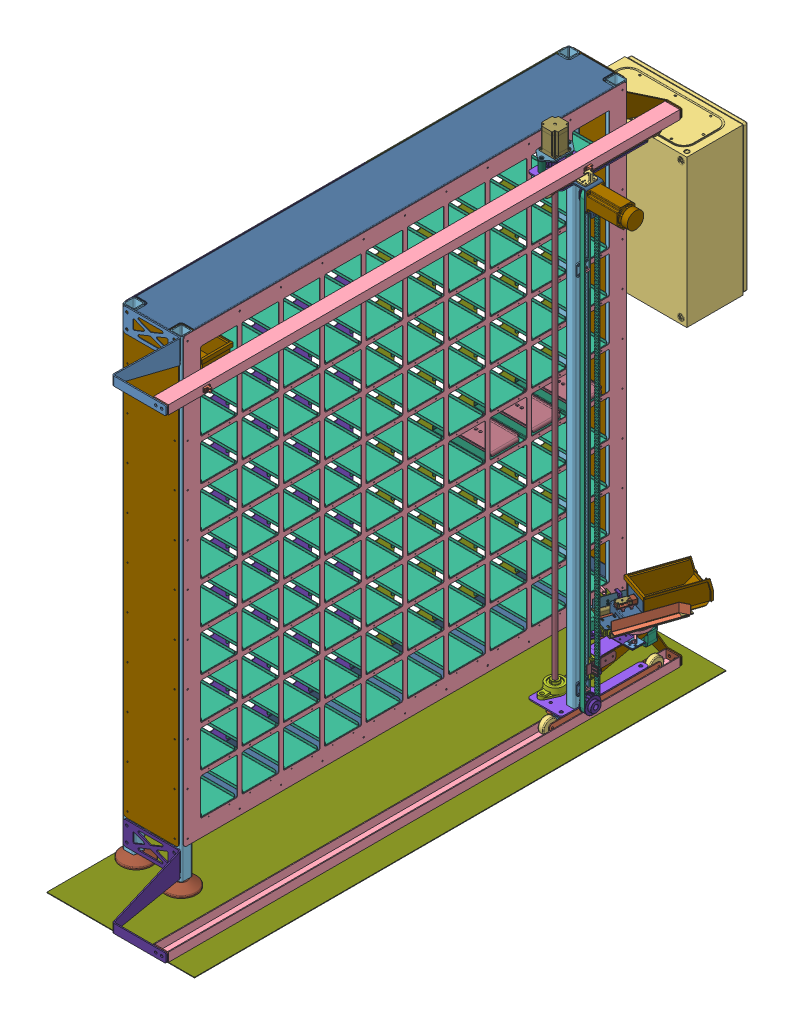
SolidWorks assembly T00000-000-R01, configuration Default. Lengths in mm.
Overall size (585.3 1705.5 1964.8).
272 component instances, 76 part files, 38 mates.
Components (placement in the parent):
- T00001-000-R00-1: T00001-000-R00 [Default] at (541.221 27.0951 939.139) size (309.78 1703.5 1800.8) (flexible)
  - T00118-000-R00-1: T00118-000-R00 [Default] at (157.9488 226.0018 -468.9511) size (25 25 300)
  - T00119-DXF-R00-1: T00119-DXF-R00 [Default] at (145.4488 226.0018 -318.9511) x (0 0 1) z (0 -1 0) size (380 3 25)
  - T00119-DXF-R00-2: T00119-DXF-R00 [Default] at (173.4488 226.0018 -318.9511) x (0 0 -1) z (0 1 0) size (380 3 25)
  - T00103-E00-R00-1: T00103-E00-R00 [Default] at (157.9488 226.0018 -138.9511) x (0 -0.996374 0.085085) z (0 0.085085 0.996374) size (50 22 50)
  - T00103-E00-R00-2: T00103-E00-R00 [Default] at (157.9488 226.0018 -498.9511) x (0 -1 0) z (0 0 1) size (50 22 50)
  - T00117-000-R00-1: T00117-000-R00 [Default] at (157.9488 198.0018 -560.9511) size (50 30 1732)
  - T00112-000-R00-1: T00112-000-R00 [50 x 30 x 2.6x1700] at (142.9488 1012.5018 -263.9511) x (1 0 0) z (0 -1 0) size (30 50 1540)
  - T00109-E00-R00-1: T00109-E00-R00 [HGR15R400CE20] at (157.9488 1772.5018 -263.9511) x (1 0 0) z (0 1 0) size (15 15 1530)
  - T00100-E00-R00-4: T00100-E00-R00 [Default] at (82.9488 242.5018 -238.9511) x (0 1 0) z (0 0 1) size (65.14 65.88 113)
  - T00120-DXF-R00-1: T00120-DXF-R00 [Default] at (100.4488 238.5018 -238.9511) x (0 0 -1) z (-1 0 0) size (300 4 115)
  - T00120-DXF-R00-2: T00120-DXF-R00 [Default] at (100.4488 1782.5018 -238.9511) x (0 0 -1) z (-1 0 0) size (300 4 115)
  - T00100-E00-R00-2: T00100-E00-R00 [Default] at (82.9488 1782.5018 -238.9511) x (0 -1 0) z (0 0 -1) size (65.14 65.88 113)
  - T00160-E00-R00-8: T00160-E00-R00 [Default] at (216.9488 1755.5018 -238.9511) x (0 0 1) z (-1 0 0) size (60 69 159.8)
  - T00121-0A4-R00-1: T00121-0A4-R00 [Default] at (216.9488 1751.5018 -238.9511) x (0 0 -1) z (0 -1 0) size (300 74 94)
  - T00103-E00-R00-3: T00103-E00-R00 [Default] at (157.9488 1803.0018 -138.9511) x (0 -1 0) z (0 0 1) size (50 22 50)
  - T00103-E00-R00-4: T00103-E00-R00 [Default] at (157.9488 1803.0018 -498.9511) x (0 0.952135 0.305677) z (0 0.305677 -0.952135) size (50 22 50)
  - T00119-DXF-R00-3: T00119-DXF-R00 [Default] at (173.4488 1803.0018 -318.9511) x (0 0 1) z (0 -1 0) size (380 3 25)
  - T00119-DXF-R00-4: T00119-DXF-R00 [Default] at (145.4488 1803.0018 -318.9511) x (0 0 -1) z (0 1 0) size (380 3 25)
  - T00118-000-R00-2: T00118-000-R00 [Default] at (157.9488 1803.0018 -168.9511) x (1 0 0) z (0 0 -1) size (25 25 300)
  - T00117-000-R00-2: T00117-000-R00 [Default] at (157.9488 1833.5018 -560.9511) x (-1 0 0) z (0 0 1) size (50 30 1732)
  - T00122-DXF-R00-1: T00122-DXF-R00 [Default] at (157.9488 213.0018 1175.0489) size (50 30 4)
  - T00122-DXF-R00-2: T00122-DXF-R00 [Default] at (157.9488 213.0018 -560.9511) size (50 30 4)
  - T00122-DXF-R00-3: T00122-DXF-R00 [Default] at (157.9488 1818.5018 -564.9511) x (-1 0 0) z (0 0 -1) size (50 30 4)
  - T00122-DXF-R00-4: T00122-DXF-R00 [Default] at (157.9488 1818.5018 1175.0489) size (50 30 4)
  - T00106-E00-R00-6: T00106-E00-R00 [Default] at (82.8989 1862.7018 -130.4663) x (-0.013505 0 0.999909) z (0 -1 0) size (56.4 57 96.6)
  - T00123-000-R00-1: T00123-000-R00 [Default] at (82.341 1823.9018 -238.9552) x (1 0 0) z (0 -1 0) size (15 15 1615)
  - T00124-DXF-R00-1: T00124-DXF-R00 [Default] at (82.341 1825.5018 -238.9552) x (-0.013505 0 0.999909) z (-0.999909 0 -0.013505) size (110 4 65)
  - T00104-E00-R00-1: T00104-E00-R00 [Default] at (82.9488 1786.5018 -193.9511) x (0 1 0) z (0 0 1) size (35 20 20)
  - T00104-E00-R00-2: T00104-E00-R00 [Default] at (82.9488 1786.5018 -283.9511) x (0 1 0) z (0 0 1) size (35 20 20)
  - T00101-E00-R00-1: T00101-E00-R00 [Default] at (112.9488 1791.0018 -193.9511) size (22 7 22)
  - T00101-E00-R00-2: T00101-E00-R00 [Default] at (112.9488 1791.0018 -283.9511) size (22 7 22)
  - T00101-E00-R00-3: T00101-E00-R00 [Default] at (112.9488 1798.0018 -283.9511) x (-0.837169 0 -0.546944) z (-0.546944 0 0.837169) size (22 7 22)
  - T00101-E00-R00-4: T00101-E00-R00 [Default] at (112.9488 1798.0018 -193.9511) x (-0.837169 0 -0.546944) z (-0.546944 0 0.837169) size (22 7 22)
  - T00101-E00-R00-5: T00101-E00-R00 [Default] at (112.9488 234.0018 -283.9511) size (22 7 22)
  - T00101-E00-R00-6: T00101-E00-R00 [Default] at (112.9488 227.0018 -283.9511) size (22 7 22)
  - T00101-E00-R00-7: T00101-E00-R00 [Default] at (112.9488 234.0018 -193.9511) x (-0.837169 0 -0.546944) z (-0.546944 0 0.837169) size (22 7 22)
  - T00101-E00-R00-8: T00101-E00-R00 [Default] at (112.9488 227.0018 -193.9511) x (-0.837169 0 -0.546944) z (-0.546944 0 0.837169) size (22 7 22)
  - T00102-E00-R00-1: T00102-E00-R00 [Default] at (82.341 237.5018 -238.9552) x (0 -1 0) z (-0.546944 0 0.837169) size (31 54 54)
  - T00102-E00-R00-2: T00102-E00-R00 [Default] at (82.341 1787.5018 -238.9552) x (0 1 0) z (0 0 1) size (31 54 54)
  - T00102-E00-R00-3: T00102-E00-R00 [Default] at (210.9488 1755.5018 -238.9511) x (-1 0 0) z (0 0.771773 0.635898) size (31 54 54)
  - T00125-0A4-R00-1: T00125-0A4-R00 [Default] at (137.9488 260.2518 -238.9511) x (0 0.966097 0.25818) z (0 0.25818 -0.966097) size (15 71.4 15)
  - T00102-E00-R00-5: T00102-E00-R00 [Default] at (189.9488 260.2518 -238.9511) x (1 0 0) z (0 0.750181 0.661232) size (31 54 54)
  - T00152-03D-R00-4: T00152-03D-R00 [Default] at (172.9488 297.5018 -239.1511) x (0 -1 0) z (0 0 1) size (40 4 40)
  - T00149-E00-R00-2: T00149-E00-R00 [Default] at (195.8488 1815.5018 -247.7511) x (0 0 1) z (0 1 0) size (22.7 14.9 13.4)
  - T00149-E00-R00-3: T00149-E00-R00 [Default] at (195.8488 1821.5018 1041.6323) x (0 0 -1) z (0 -1 0) size (22.7 14.9 13.4)
  - T00150-03D-R00-3: T00150-03D-R00 [Default] at (191.1488 1790.5018 -238.9511) x (0 0 -1) z (1 0 0) size (45 29.75 32)
  - T00153-E00-R00-1: T00153-E00-R00 [Default] at (180.9488 1523.996 -248.1511) x (0 -1 0) z (1 0 0) size (13 22.4 13.7)
  - T00151-03D-R00-1: T00151-03D-R00 [Default] at (172.9488 1527.496 -238.9511) x (0 -1 0) z (0 0 1) size (40 4 40)
  - T00153-E00-R00-2: T00153-E00-R00 [Default] at (180.9488 294.0018 -247.9534) x (0 -1 0) z (1 0 0) size (13 22.4 13.7)
  - T00166-E00-R00-1: T00166-E00-R00 [Default] at (193.6988 1755.5018 106.6406) x (0 0 -1) z (1 0 0) size (52.05 1547.3 15)
  - T00003-000-R02-2: T00003-000-R02 [Default] at (0 -530.7546 -533.6254) size (206.44 185.95 380.78)
    - T00108-E00-R00-3: T00108-E00-R00 [Default] at (157.9488 862.2474 269.7743) x (1 0 0) z (0 1 0) size (34 23.7 61.49)
    - T00110-E00-R00-1: T00110-E00-R00 [HGR15R400CE20] at (220.7447 918.7474 -18.1171) x (-0.945846 0 -0.324616) z (0.324616 0 -0.945846) size (15 15 270)
    - T00108-E00-R00-4: T00108-E00-R00 [Default] at (154.4543 918.7474 175.0355) x (-0.945846 0 -0.324616) z (0.324616 0 -0.945846) size (34 23.7 61.49)
    - T00148-E00-R00-1: T00148-E00-R00 [Default] at (206.0289 941.2474 119.0644) x (-0.945846 0 -0.324616) z (0.324616 0 -0.945846) size (104.77 76.2 187.32)
    - T00006-000-R00-1: T00006-000-R00 [Default] at (104.8241 969.1581 159.4141) x (-0.945846 0 -0.324616) z (0 -1 0) size (100 103 92)
      - T00126-000-R02-1: T00126-000-R02 [Default] at (-76.7384 90.3354 70.4106) size (82 103 92)
      - T00005-000-R00-1: T00005-000-R00 [Default] at (-79.4687 62.4093 14.8739) x (0 -1 0) z (1 0 0) size (53.8 27.95 21.5)
        - T00154-E00-R01-1: T00154-E00-R01 [Default] at (15.674 22.2087 43.7303) size (53.8 16.25 21.5)
        - T00172-000-R01-1: T00172-000-R01 [Default] at (22.774 33.8087 43.7303) size (39 12 21.5)
        - T00171-000-R01-1: T00171-000-R01 [Default] at (15.674 10.2087 43.7303) size (53.2 12 21.5)
        - T00173-000-R01-1: T00173-000-R01 [Default] at (25.474 28.1587 43.0803) size (6 10 6)
        - socket head cap screw_iso-1: socket head cap screw_iso [ISO 4762 M2 x 16 - 16C] at (40.074 37.8087 51.9803) x (0 -1 0) z (0 0 1) size (18 3.8 3.8)
        - socket head cap screw_iso-4: socket head cap screw_iso [ISO 4762 M2 x 16 - 16C] at (5.074 37.8087 51.9803) x (0 -1 0) z (0 0 1) size (18 3.8 3.8)
        - socket head cap screw_iso-5: socket head cap screw_iso [ISO 4762 M2 x 16 - 16C] at (40.074 37.8087 35.4803) x (0 -1 0) z (0 0 1) size (18 3.8 3.8)
      - socket head cap screw_iso-1: socket head cap screw_iso [ISO 4762 M3 x 16 - 16C] at (-35.7384 58.3354 -6.3347) x (0 0 1) z (0 -1 0) size (19 5.5 5.5)
      - socket head cap screw_iso-2: socket head cap screw_iso [ISO 4762 M3 x 16 - 16C] at (-35.7384 35.3354 -6.3347) x (0 0 1) z (0 -1 0) size (19 5.5 5.5)
      - hex thin nut chamfered gradeab_iso-1: hex thin nut chamfered gradeab_iso [ISO - 4035 - M3 - C] at (-35.7384 35.3354 8.4653) size (5.5 6.35 1.8)
      - hex thin nut chamfered gradeab_iso-2: hex thin nut chamfered gradeab_iso [ISO - 4035 - M3 - C] at (-35.7384 58.3354 8.4653) size (5.5 6.35 1.8)
      - T00163-03D-R01-1: T00163-03D-R01 [Default] at (-4.7384 50.3354 4.6653) x (1 0 0) z (0 0 -1) size (38 30 18.2)
      - socket countersunk head screw_iso-1: socket countersunk head screw_iso [ISO 10642 - M3 x 8 - 8C] at (-9.7384 59.3354 1.6553) x (0 0 1) z (0.923728 0.383049 0) size (8 5.54 5.54)
      - socket countersunk head screw_iso-2: socket countersunk head screw_iso [ISO 10642 - M3 x 8 - 8C] at (-9.7384 41.3354 1.6553) x (0 0 1) z (0.923728 0.383049 0) size (8 5.54 5.54)
      - hex thin nut chamfered gradeab_iso-5: hex thin nut chamfered gradeab_iso [ISO - 4035 - M3 - C] at (-9.7384 41.3354 8.4653) size (5.5 6.35 1.8)
      - hex thin nut chamfered gradeab_iso-6: hex thin nut chamfered gradeab_iso [ISO - 4035 - M3 - C] at (-9.7384 59.3354 8.4653) size (5.5 6.35 1.8)
    - T00127-E00-R00-1: T00127-E00-R00 [DIN 625 - 6002 - 12,SI,NC,12_68] at (157.9488 901.2474 97.7743) x (0 1 0) z (0 0 1) size (9 32 32)
    - T00128-0A4-R00-1: T00128-0A4-R00 [Default] at (157.9488 887.7474 97.7743) x (1 0 0) z (0 -1 0) size (25 25 21)
    - T00129-E00-R00-1: T00129-E00-R00 [Circlip DIN 471 - 15 x 1.5] at (157.9488 905.9474 97.7743) x (0.837169 0 0.546944) z (0 -1 0) size (17.74 21.49 1.5)
    - T00130-0A4-R01-1: T00130-0A4-R01 [Default] at (157.9488 895.7474 97.7743) x (0.324616 0 -0.945846) z (0 -1 0) size (90 90 20)
    - T00132-E00-R00-4: T00132-E00-R00 [Metric - Spur gear 1M 60T 20PA 9FW ---S60N75H50L42N] at (157.9488 896.7474 97.7743) x (0 1 0) z (0 0 1) size (9 61.95 61.95)
    - T00107-E00-R00-1: T00107-E00-R00 [Varsayılan] at (157.9488 879.7474 61.7743) x (-1 0 0) z (0 1 0) size (42 58.5 65.65)
    - T00131-E00-R00-2: T00131-E00-R00 [Metric - Spur gear 1M 12T 20PA 8FW ---S12O10H14L5N] at (157.9488 896.7474 61.7743) x (0 1 0) z (0.924225 0 0.381849) size (14 13.61 13.61)
    - T00133-0A4-R00-3: T00133-0A4-R00 [Default] at (157.9488 862.2474 237.7743) x (1 0 0) z (0 1 0) size (49 210 57)
    - T00134-DXF-R00-1: T00134-DXF-R00 [Default] at (130.4488 892.7474 239.7743) x (0 0 -1) z (-1 0 0) size (155 44.25 3)
    - T00134-DXF-R00-2: T00134-DXF-R00 [Default] at (182.4488 892.7474 239.7743) x (0 0 -1) z (-1 0 0) size (155 44.25 3)
    - T00105-E00-R00-1: T00105-E00-R00 [Default] at (142.4488 890.7474 46.2743) x (1 0 0) z (0 -1 0) size (6 6 11)
    - T00105-E00-R00-2: T00105-E00-R00 [Default] at (173.4488 890.7474 46.2743) x (0.974973 0 -0.222324) z (0 -1 0) size (6 6 11)
    - T00105-E00-R00-3: T00105-E00-R00 [Default] at (142.4488 890.7474 77.2743) x (1 0 0) z (0 -1 0) size (6 6 11)
    - T00105-E00-R00-4: T00105-E00-R00 [Default] at (173.4488 890.7474 77.2743) x (1 0 0) z (0 -1 0) size (6 6 11)
    - T00107-E00-R00-2: T00107-E00-R00 [Varsayılan] at (104.3679 933.2474 184.5821) x (0.945846 0 0.324616) z (0.324616 0 -0.945846) size (42 58.5 65.65)
    - T00111-E00-R00-1: T00111-E00-R00 [Default] at (182.9251 933.2474 -44.3126) x (-0.536568 -0.823519 -0.184151) z (-0.778922 0.567289 -0.267328) size (10 240 10)
    - T00135-DXF-R01-1: T00135-DXF-R01 [Default] at (162.818 918.7474 83.5866) x (-0.324616 0 0.945846) z (-0.945846 0 -0.324616) size (219 39 131)
    - T00136-DXF-R01-1: T00136-DXF-R01 [Default] at (187.4488 877.7474 233.7743) x (0 0 -1) z (1 0 0) size (94.88 30 25)
    - T00138-000-R00-1: T00138-000-R00 [gespiegeld] at (139.5613 941.2474 -4.2179) x (0.324616 0 -0.945846) z (0.945846 0 0.324616) size (201.93 32 21.92)
    - T00153-E00-R00-4: T00153-E00-R00 [Default] at (89.0052 977.2474 133.8476) x (-0.324616 0 0.945846) z (0 1 0) size (13 22.4 13.7)
    - socket head cap screw_iso-1: socket head cap screw_iso [ISO 4762 M3 x 16 - 16N] at (76.144 978.7474 122.0328) x (0 -1 0) z (0.992143 0 0.125105) size (19 5.5 5.5)
    - hex nut style 1 gradeab_iso-1: hex nut style 1 gradeab_iso [ISO - 4032 - M3 - W - N] at (76.144 965.2474 122.0328) x (0.998096 0 0.061684) z (0 1 0) size (5.5 6.35 2.4)
    - socket head cap screw_iso-2: socket head cap screw_iso [ISO 4762 M3 x 16 - 16N] at (82.7649 978.7474 124.3052) x (0 -1 0) z (-0.061684 0 0.998096) size (19 5.5 5.5)
    - socket head cap screw_iso-3: socket head cap screw_iso [ISO 4762 M3 x 8 - 8N] at (86.5483 949.2474 125.6036) x (0.945846 0 0.324616) z (-0.316094 -0.227635 0.921014) size (11 5.5 5.5)
    - socket head cap screw_iso-4: socket head cap screw_iso [ISO 4762 M3 x 8 - 8N] at (86.5483 957.2474 125.6036) x (0.945846 0 0.324616) z (-0.159414 -0.871112 0.46449) size (11 5.5 5.5)
    - hex nut style 1 gradeab_iso-3: hex nut style 1 gradeab_iso [ISO - 4032 - M3 - W - N] at (82.7649 965.5626 124.3052) x (0.95019 0 0.311672) z (0 1 0) size (5.5 6.35 2.4)
    - hex nut style 1 gradeab_iso-4: hex nut style 1 gradeab_iso [ISO - 4032 - M3 - W - N] at (94.115 957.2474 128.2005) x (0.159414 0.871112 -0.46449) z (-0.945846 0 -0.324616) size (5.5 6.35 2.4)
    - hex nut style 1 gradeab_iso-5: hex nut style 1 gradeab_iso [ISO - 4032 - M3 - W - N] at (94.115 949.2474 128.2005) x (0.159414 0.871112 -0.46449) z (-0.945846 0 -0.324616) size (5.5 6.35 2.4)
    - T00153-E00-R00-7: T00153-E00-R00 [Default] at (120.7549 900.9974 134.9681) x (0.707107 0 0.707107) z (0 1 0) size (13 22.4 13.7)
    - T00153-E00-R00-8: T00153-E00-R00 [Default] at (195.1426 900.9974 134.9681) x (0.707107 0 -0.707107) z (0 1 0) size (13 22.4 13.7)
    - T00168-03D-R00-2: T00168-03D-R00 [Default] at (93.1692 959.2474 127.8759) x (-0.324616 0 0.945846) z (-0.945846 0 -0.324616) size (20 28 25.65)
    - T00161-0A4-R00-2: T00161-0A4-R00 [Default] at (157.9488 894.7474 147.7835) size (125 2 45)
    - T00164-03D-R00-1: T00164-03D-R00 [Default] at (157.9488 896.7474 147.7835) x (1 0 0) z (0 1 0) size (32 42.2 3)
    - T00165-03D-R00-1: T00165-03D-R00 [Default] at (250.9488 896.7474 147.7835) x (1 0 0) z (0 1 0) size (32 42.2 3)
    - T00137-000-R00-2: T00137-000-R00 [gespiegeld] at (236.0376 941.2474 28.893) x (0.324616 0 -0.945846) z (0.945846 0 0.324616) size (201.93 32 21.92)
    - T00162-03D-R03-1: T00162-03D-R03 [Default] at (174.1796 915.7474 50.482) x (-0.945846 0 -0.324616) z (0 -1 0) size (28 24.69 9)
- T00002-000-R00-1: T00002-000-R00 [Default] at (-702.7967 301.9782 1483.2641) x (0 0 -1) z (1 0 0) size (1575.8 1630 263)
  - T00114-DXF-R00-1: T00114-DXF-R00 [Default] at (354.4761 803.1187 1246.9664) size (1500 1500 2)
  - T00113-000-R00-9: T00113-000-R00 [40 x 40 x 3.2x1600] at (1070.8761 753.1187 1084.9664) x (0 0 -1) z (0 -1 0) size (40 40 1600)
  - T00113-000-R00-6: T00113-000-R00 [40 x 40 x 3.2x1600] at (-401.9239 753.1187 1204.9664) x (1 0 0) z (0 -1 0) size (40 40 1600)
  - T00113-000-R00-10: T00113-000-R00 [40 x 40 x 3.2x1600] at (-401.9239 753.1187 1084.9664) x (1 0 0) z (0 1 0) size (40 40 1600)
  - T00113-000-R00-8: T00113-000-R00 [40 x 40 x 3.2x1600] at (1070.8761 753.1187 1244.9664) x (1 0 0) z (0 1 0) size (40 40 1600)
  - T00116-0A4-R00-1: T00116-0A4-R00 [Default] at (-275.5239 1370.6187 1144.9664) x (0 0 -1) z (0 -1 0) size (200 114 23)
  - T00116-0A4-R00-2: T00116-0A4-R00 [Default] at (-275.5239 1230.6187 1144.9664) x (0 0 -1) z (0 -1 0) size (200 114 23)
  - T00116-0A4-R00-3: T00116-0A4-R00 [Default] at (-275.5239 1090.6187 1144.9664) x (0 0 -1) z (0 -1 0) size (200 114 23)
  - T00116-0A4-R00-4: T00116-0A4-R00 [Default] at (-275.5239 950.6187 1144.9664) x (0 0 -1) z (0 -1 0) size (200 114 23)
  - T00116-0A4-R00-5: T00116-0A4-R00 [Default] at (-275.5239 810.6187 1144.9664) x (0 0 -1) z (0 -1 0) size (200 114 23)
  - T00116-0A4-R00-6: T00116-0A4-R00 [Default] at (-275.5239 670.6187 1144.9664) x (0 0 -1) z (0 -1 0) size (200 114 23)
  - T00116-0A4-R00-7: T00116-0A4-R00 [Default] at (-275.5239 530.6187 1144.9664) x (0 0 -1) z (0 -1 0) size (200 114 23)
  - T00116-0A4-R00-8: T00116-0A4-R00 [Default] at (-275.5239 390.6187 1144.9664) x (0 0 -1) z (0 -1 0) size (200 114 23)
  - T00116-0A4-R00-9: T00116-0A4-R00 [Default] at (-275.5239 250.6187 1144.9664) x (0 0 -1) z (0 -1 0) size (200 114 23)
  - T00116-0A4-R00-10: T00116-0A4-R00 [Default] at (-275.5239 110.6187 1144.9664) x (0 0 -1) z (0 -1 0) size (200 114 23)
  - T00116-0A4-R00-11: T00116-0A4-R00 [Default] at (-135.5239 1370.6187 1144.9664) x (0 0 -1) z (0 -1 0) size (200 114 23)
  - T00116-0A4-R00-12: T00116-0A4-R00 [Default] at (-135.5239 1230.6187 1144.9664) x (0 0 -1) z (0 -1 0) size (200 114 23)
  - T00116-0A4-R00-13: T00116-0A4-R00 [Default] at (-135.5239 1090.6187 1144.9664) x (0 0 -1) z (0 -1 0) size (200 114 23)
  - T00116-0A4-R00-14: T00116-0A4-R00 [Default] at (-135.5239 950.6187 1144.9664) x (0 0 -1) z (0 -1 0) size (200 114 23)
  - T00116-0A4-R00-15: T00116-0A4-R00 [Default] at (-135.5239 810.6187 1144.9664) x (0 0 -1) z (0 -1 0) size (200 114 23)
  - T00116-0A4-R00-16: T00116-0A4-R00 [Default] at (-135.5239 670.6187 1144.9664) x (0 0 -1) z (0 -1 0) size (200 114 23)
  - T00116-0A4-R00-17: T00116-0A4-R00 [Default] at (-135.5239 530.6187 1144.9664) x (0 0 -1) z (0 -1 0) size (200 114 23)
  - T00116-0A4-R00-18: T00116-0A4-R00 [Default] at (-135.5239 390.6187 1144.9664) x (0 0 -1) z (0 -1 0) size (200 114 23)
  - T00116-0A4-R00-19: T00116-0A4-R00 [Default] at (-135.5239 250.6187 1144.9664) x (0 0 -1) z (0 -1 0) size (200 114 23)
  - T00116-0A4-R00-20: T00116-0A4-R00 [Default] at (-135.5239 110.6187 1144.9664) x (0 0 -1) z (0 -1 0) size (200 114 23)
  - T00116-0A4-R00-21: T00116-0A4-R00 [Default] at (4.4761 1370.6187 1144.9664) x (0 0 -1) z (0 -1 0) size (200 114 23)
  - T00116-0A4-R00-22: T00116-0A4-R00 [Default] at (4.4761 1230.6187 1144.9664) x (0 0 -1) z (0 -1 0) size (200 114 23)
  - T00116-0A4-R00-23: T00116-0A4-R00 [Default] at (4.4761 1090.6187 1144.9664) x (0 0 -1) z (0 -1 0) size (200 114 23)
  - T00116-0A4-R00-24: T00116-0A4-R00 [Default] at (4.4761 950.6187 1144.9664) x (0 0 -1) z (0 -1 0) size (200 114 23)
  - T00116-0A4-R00-25: T00116-0A4-R00 [Default] at (4.4761 810.6187 1144.9664) x (0 0 -1) z (0 -1 0) size (200 114 23)
  - T00116-0A4-R00-26: T00116-0A4-R00 [Default] at (4.4761 670.6187 1144.9664) x (0 0 -1) z (0 -1 0) size (200 114 23)
  - T00116-0A4-R00-27: T00116-0A4-R00 [Default] at (4.4761 530.6187 1144.9664) x (0 0 -1) z (0 -1 0) size (200 114 23)
  - T00116-0A4-R00-28: T00116-0A4-R00 [Default] at (4.4761 390.6187 1144.9664) x (0 0 -1) z (0 -1 0) size (200 114 23)
  - T00116-0A4-R00-29: T00116-0A4-R00 [Default] at (4.4761 250.6187 1144.9664) x (0 0 -1) z (0 -1 0) size (200 114 23)
  - T00116-0A4-R00-30: T00116-0A4-R00 [Default] at (4.4761 110.6187 1144.9664) x (0 0 -1) z (0 -1 0) size (200 114 23)
  - T00116-0A4-R00-31: T00116-0A4-R00 [Default] at (144.4761 1370.6187 1144.9664) x (0 0 -1) z (0 -1 0) size (200 114 23)
  - T00116-0A4-R00-32: T00116-0A4-R00 [Default] at (144.4761 1230.6187 1144.9664) x (0 0 -1) z (0 -1 0) size (200 114 23)
  - T00116-0A4-R00-33: T00116-0A4-R00 [Default] at (144.4761 1090.6187 1144.9664) x (0 0 -1) z (0 -1 0) size (200 114 23)
  - T00116-0A4-R00-34: T00116-0A4-R00 [Default] at (144.4761 950.6187 1144.9664) x (0 0 -1) z (0 -1 0) size (200 114 23)
  - T00116-0A4-R00-35: T00116-0A4-R00 [Default] at (144.4761 810.6187 1144.9664) x (0 0 -1) z (0 -1 0) size (200 114 23)
  - T00116-0A4-R00-36: T00116-0A4-R00 [Default] at (144.4761 670.6187 1144.9664) x (0 0 -1) z (0 -1 0) size (200 114 23)
  - T00116-0A4-R00-37: T00116-0A4-R00 [Default] at (144.4761 530.6187 1144.9664) x (0 0 -1) z (0 -1 0) size (200 114 23)
  - T00116-0A4-R00-38: T00116-0A4-R00 [Default] at (144.4761 390.6187 1144.9664) x (0 0 -1) z (0 -1 0) size (200 114 23)
  - T00116-0A4-R00-39: T00116-0A4-R00 [Default] at (144.4761 250.6187 1144.9664) x (0 0 -1) z (0 -1 0) size (200 114 23)
  - T00116-0A4-R00-40: T00116-0A4-R00 [Default] at (144.4761 110.6187 1144.9664) x (0 0 -1) z (0 -1 0) size (200 114 23)
  - T00116-0A4-R00-41: T00116-0A4-R00 [Default] at (284.4761 1370.6187 1144.9664) x (0 0 -1) z (0 -1 0) size (200 114 23)
  - T00116-0A4-R00-42: T00116-0A4-R00 [Default] at (284.4761 1230.6187 1144.9664) x (0 0 -1) z (0 -1 0) size (200 114 23)
  - T00116-0A4-R00-43: T00116-0A4-R00 [Default] at (284.4761 1090.6187 1144.9664) x (0 0 -1) z (0 -1 0) size (200 114 23)
  - T00116-0A4-R00-44: T00116-0A4-R00 [Default] at (284.4761 950.6187 1144.9664) x (0 0 -1) z (0 -1 0) size (200 114 23)
  - T00116-0A4-R00-45: T00116-0A4-R00 [Default] at (284.4761 810.6187 1144.9664) x (0 0 -1) z (0 -1 0) size (200 114 23)
  - T00116-0A4-R00-46: T00116-0A4-R00 [Default] at (284.4761 670.6187 1144.9664) x (0 0 -1) z (0 -1 0) size (200 114 23)
  - T00116-0A4-R00-47: T00116-0A4-R00 [Default] at (284.4761 530.6187 1144.9664) x (0 0 -1) z (0 -1 0) size (200 114 23)
  - T00116-0A4-R00-48: T00116-0A4-R00 [Default] at (284.4761 390.6187 1144.9664) x (0 0 -1) z (0 -1 0) size (200 114 23)
  - T00116-0A4-R00-49: T00116-0A4-R00 [Default] at (284.4761 250.6187 1144.9664) x (0 0 -1) z (0 -1 0) size (200 114 23)
  - T00116-0A4-R00-50: T00116-0A4-R00 [Default] at (284.4761 110.6187 1144.9664) x (0 0 -1) z (0 -1 0) size (200 114 23)
  - T00116-0A4-R00-51: T00116-0A4-R00 [Default] at (424.4761 1370.6187 1144.9664) x (0 0 -1) z (0 -1 0) size (200 114 23)
  - T00116-0A4-R00-52: T00116-0A4-R00 [Default] at (424.4761 1230.6187 1144.9664) x (0 0 -1) z (0 -1 0) size (200 114 23)
  - T00116-0A4-R00-53: T00116-0A4-R00 [Default] at (424.4761 1090.6187 1144.9664) x (0 0 -1) z (0 -1 0) size (200 114 23)
  - T00116-0A4-R00-54: T00116-0A4-R00 [Default] at (424.4761 950.6187 1144.9664) x (0 0 -1) z (0 -1 0) size (200 114 23)
  - T00116-0A4-R00-55: T00116-0A4-R00 [Default] at (424.4761 810.6187 1144.9664) x (0 0 -1) z (0 -1 0) size (200 114 23)
  - T00116-0A4-R00-56: T00116-0A4-R00 [Default] at (424.4761 670.6187 1144.9664) x (0 0 -1) z (0 -1 0) size (200 114 23)
  - T00116-0A4-R00-57: T00116-0A4-R00 [Default] at (424.4761 530.6187 1144.9664) x (0 0 -1) z (0 -1 0) size (200 114 23)
  - T00116-0A4-R00-58: T00116-0A4-R00 [Default] at (424.4761 390.6187 1144.9664) x (0 0 -1) z (0 -1 0) size (200 114 23)
  - T00116-0A4-R00-59: T00116-0A4-R00 [Default] at (424.4761 250.6187 1144.9664) x (0 0 -1) z (0 -1 0) size (200 114 23)
  - T00116-0A4-R00-60: T00116-0A4-R00 [Default] at (424.4761 110.6187 1144.9664) x (0 0 -1) z (0 -1 0) size (200 114 23)
  - T00116-0A4-R00-61: T00116-0A4-R00 [Default] at (564.4761 1370.6187 1144.9664) x (0 0 -1) z (0 -1 0) size (200 114 23)
  - T00116-0A4-R00-62: T00116-0A4-R00 [Default] at (564.4761 1230.6187 1144.9664) x (0 0 -1) z (0 -1 0) size (200 114 23)
  - T00116-0A4-R00-63: T00116-0A4-R00 [Default] at (564.4761 1090.6187 1144.9664) x (0 0 -1) z (0 -1 0) size (200 114 23)
  - T00116-0A4-R00-64: T00116-0A4-R00 [Default] at (564.4761 950.6187 1144.9664) x (0 0 -1) z (0 -1 0) size (200 114 23)
  - T00116-0A4-R00-65: T00116-0A4-R00 [Default] at (564.4761 810.6187 1144.9664) x (0 0 -1) z (0 -1 0) size (200 114 23)
  - T00116-0A4-R00-66: T00116-0A4-R00 [Default] at (564.4761 670.6187 1144.9664) x (0 0 -1) z (0 -1 0) size (200 114 23)
  - T00116-0A4-R00-67: T00116-0A4-R00 [Default] at (564.4761 530.6187 1144.9664) x (0 0 -1) z (0 -1 0) size (200 114 23)
  - T00116-0A4-R00-68: T00116-0A4-R00 [Default] at (564.4761 390.6187 1144.9664) x (0 0 -1) z (0 -1 0) size (200 114 23)
  - T00116-0A4-R00-69: T00116-0A4-R00 [Default] at (564.4761 250.6187 1144.9664) x (0 0 -1) z (0 -1 0) size (200 114 23)
  - T00116-0A4-R00-70: T00116-0A4-R00 [Default] at (564.4761 110.6187 1144.9664) x (0 0 -1) z (0 -1 0) size (200 114 23)
  - T00116-0A4-R00-71: T00116-0A4-R00 [Default] at (704.4761 1370.6187 1144.9664) x (0 0 -1) z (0 -1 0) size (200 114 23)
  - T00116-0A4-R00-72: T00116-0A4-R00 [Default] at (704.4761 1230.6187 1144.9664) x (0 0 -1) z (0 -1 0) size (200 114 23)
  - T00116-0A4-R00-73: T00116-0A4-R00 [Default] at (704.4761 1090.6187 1144.9664) x (0 0 -1) z (0 -1 0) size (200 114 23)
  - T00116-0A4-R00-74: T00116-0A4-R00 [Default] at (704.4761 950.6187 1144.9664) x (0 0 -1) z (0 -1 0) size (200 114 23)
  - T00116-0A4-R00-75: T00116-0A4-R00 [Default] at (704.4761 810.6187 1144.9664) x (0 0 -1) z (0 -1 0) size (200 114 23)
  - T00116-0A4-R00-77: T00116-0A4-R00 [Default] at (704.4761 530.6187 1144.9664) x (0 0 -1) z (0 -1 0) size (200 114 23)
  - T00116-0A4-R00-78: T00116-0A4-R00 [Default] at (704.4761 390.6187 1144.9664) x (0 0 -1) z (0 -1 0) size (200 114 23)
  - T00116-0A4-R00-79: T00116-0A4-R00 [Default] at (704.4761 250.6187 1144.9664) x (0 0 -1) z (0 -1 0) size (200 114 23)
  - T00116-0A4-R00-80: T00116-0A4-R00 [Default] at (704.4761 110.6187 1144.9664) x (0 0 -1) z (0 -1 0) size (200 114 23)
  - T00116-0A4-R00-81: T00116-0A4-R00 [Default] at (844.4761 1370.6187 1144.9664) x (0 0 -1) z (0 -1 0) size (200 114 23)
  - T00116-0A4-R00-82: T00116-0A4-R00 [Default] at (844.4761 1230.6187 1144.9664) x (0 0 -1) z (0 -1 0) size (200 114 23)
  - T00116-0A4-R00-83: T00116-0A4-R00 [Default] at (844.4761 1090.6187 1144.9664) x (0 0 -1) z (0 -1 0) size (200 114 23)
  - T00116-0A4-R00-84: T00116-0A4-R00 [Default] at (844.4761 950.6187 1144.9664) x (0 0 -1) z (0 -1 0) size (200 114 23)
  - T00116-0A4-R00-85: T00116-0A4-R00 [Default] at (844.4761 810.6187 1144.9664) x (0 0 -1) z (0 -1 0) size (200 114 23)
  - T00116-0A4-R00-87: T00116-0A4-R00 [Default] at (844.4761 530.6187 1144.9664) x (0 0 -1) z (0 -1 0) size (200 114 23)
  - T00116-0A4-R00-88: T00116-0A4-R00 [Default] at (844.4761 390.6187 1144.9664) x (0 0 -1) z (0 -1 0) size (200 114 23)
  - T00116-0A4-R00-89: T00116-0A4-R00 [Default] at (844.4761 250.6187 1144.9664) x (0 0 -1) z (0 -1 0) size (200 114 23)
  - T00116-0A4-R00-90: T00116-0A4-R00 [Default] at (844.4761 110.6187 1144.9664) x (0 0 -1) z (0 -1 0) size (200 114 23)
  - T00116-0A4-R00-91: T00116-0A4-R00 [Default] at (984.4761 1370.6187 1144.9664) x (0 0 -1) z (0 -1 0) size (200 114 23)
  - T00116-0A4-R00-92: T00116-0A4-R00 [Default] at (984.4761 1230.6187 1144.9664) x (0 0 -1) z (0 -1 0) size (200 114 23)
  - T00116-0A4-R00-93: T00116-0A4-R00 [Default] at (984.4761 1090.6187 1144.9664) x (0 0 -1) z (0 -1 0) size (200 114 23)
  - T00116-0A4-R00-94: T00116-0A4-R00 [Default] at (984.4761 950.6187 1144.9664) x (0 0 -1) z (0 -1 0) size (200 114 23)
  - T00116-0A4-R00-95: T00116-0A4-R00 [Default] at (984.4761 810.6187 1144.9664) x (0 0 -1) z (0 -1 0) size (200 114 23)
  - T00116-0A4-R00-97: T00116-0A4-R00 [Default] at (984.4761 530.6187 1144.9664) x (0 0 -1) z (0 -1 0) size (200 114 23)
  - T00116-0A4-R00-98: T00116-0A4-R00 [Default] at (984.4761 390.6187 1144.9664) x (0 0 -1) z (0 -1 0) size (200 114 23)
  - T00116-0A4-R00-99: T00116-0A4-R00 [Default] at (984.4761 250.6187 1144.9664) x (0 0 -1) z (0 -1 0) size (200 114 23)
  - T00116-0A4-R00-100: T00116-0A4-R00 [Default] at (984.4761 110.6187 1144.9664) x (0 0 -1) z (0 -1 0) size (200 114 23)
  - T00115-DXF-R01-1: T00115-DXF-R01 [Default] at (870.8674 -111.1162 2345.3532) x (-1 0 0) z (0 0 -1) size (1500 1500 2)
    - T00158-DXF-R00-1: T00158-DXF-R00 [Default] at (516.3913 914.2349 1302.3867) size (680 1500 2)
    - T00159-DXF-R00-1: T00159-DXF-R00 [Default] at (516.3913 914.2349 1302.3867) size (820 1500 2)
  - T00139-DXF-R00-1: T00139-DXF-R00 [Default] at (1112.8761 53.1187 1238.5664) x (0 0 -1) z (1 0 0) size (187.2 1500 2)
  - T00139-DXF-R00-2: T00139-DXF-R00 [Default] at (-403.9239 53.1187 1051.3664) x (0 0 1) z (-1 0 0) size (187.2 1500 2)
  - T00140-0A4-R00-1: T00140-0A4-R00 [Default] at (354.4761 1551.1187 1144.9664) x (1 0 0) z (0 -1 0) size (1512.8 200 40)
  - T00140-0A4-R00-2: T00140-0A4-R00 [Default] at (354.4761 55.1187 1144.9664) x (1 0 0) z (0 1 0) size (1512.8 200 40)
  - T00141-E00-R00-1: T00141-E00-R00 [SINGLE NUT] at (-374.1239 -76.8813 1065.1664) size (103 100 103)
  - T00141-E00-R00-2: T00141-E00-R00 [SINGLE NUT] at (-381.9239 -76.8813 1224.9664) size (103 100 103)
  - T00141-E00-R00-3: T00141-E00-R00 [SINGLE NUT] at (1090.8761 -76.8813 1064.9664) size (103 100 103)
  - T00141-E00-R00-4: T00141-E00-R00 [SINGLE NUT] at (1090.8761 -76.8813 1224.9664) size (103 100 103)
  - T00004-000-R00-1: T00004-000-R00 [Default] at (704.4761 655.6187 1144.9664) size (114 38.3 200)
    - T00157-E00-R00-1: T00157-E00-R00 [Default] at (0 9.15 27.5) x (0 0 -1) z (-1 0 0) size (80 12.7 12.7)
    - T00156-000-R00-1: T00156-000-R00 [Default] at (0 20.3 0) x (-1 0 0) z (0 1 0) size (106 182 17)
    - flat washer narrow_am-1: flat washer narrow_am [B18.22M - Plain washer, 5 mm, narrow] at (0 2.8 62.5) x (0 1 0) z (0 0 1) size (1.4 11 11)
    - flat washer narrow_am-2: flat washer narrow_am [B18.22M - Plain washer, 5 mm, narrow] at (0 2.8 47.5) x (0 1 0) z (0 0 1) size (1.4 11 11)
    - flat washer narrow_am-3: flat washer narrow_am [B18.22M - Plain washer, 5 mm, narrow] at (0 1.4 62.5) x (0 1 0) z (0 0 1) size (1.4 11 11)
    - flat washer narrow_am-4: flat washer narrow_am [B18.22M - Plain washer, 5 mm, narrow] at (0 1.4 47.5) x (0 1 0) z (-0.546944 0 0.837169) size (1.4 11 11)
    - flat washer narrow_am-7: flat washer narrow_am [B18.22M - Plain washer, 5 mm, narrow] at (0 15.5 -7.5) x (0 -1 0) z (-0.546944 0 0.837169) size (1.4 11 11)
    - flat washer narrow_am-8: flat washer narrow_am [B18.22M - Plain washer, 5 mm, narrow] at (0 16.9 -7.5) x (0 -1 0) z (0 0 1) size (1.4 11 11)
    - flat washer narrow_am-11: flat washer narrow_am [B18.22M - Plain washer, 5 mm, narrow] at (0 15.5 7.5) x (0 -1 0) z (-0.535309 0 -0.844656) size (1.4 11 11)
    - flat washer narrow_am-12: flat washer narrow_am [B18.22M - Plain washer, 5 mm, narrow] at (0 16.9 7.5) x (0 -1 0) z (0 0 1) size (1.4 11 11)
    - T00155-0A3-R00-3: T00155-0A3-R00 [Default] x (0 0 -1) z (0 1 0) size (200 114 23)
  - T00004-000-R00-2: T00004-000-R00 [Default] at (844.4761 655.6187 1144.9664) size (114 38.3 200)
    - T00157-E00-R00-1: T00157-E00-R00 [Default] at (0 9.15 27.5) x (0 0 -1) z (-1 0 0) size (80 12.7 12.7)
    - T00156-000-R00-1: T00156-000-R00 [Default] at (0 20.3 0) x (-1 0 0) z (0 1 0) size (106 182 17)
    - flat washer narrow_am-1: flat washer narrow_am [B18.22M - Plain washer, 5 mm, narrow] at (0 2.8 62.5) x (0 1 0) z (0 0 1) size (1.4 11 11)
    - flat washer narrow_am-2: flat washer narrow_am [B18.22M - Plain washer, 5 mm, narrow] at (0 2.8 47.5) x (0 1 0) z (0 0 1) size (1.4 11 11)
    - flat washer narrow_am-3: flat washer narrow_am [B18.22M - Plain washer, 5 mm, narrow] at (0 1.4 62.5) x (0 1 0) z (0 0 1) size (1.4 11 11)
    - flat washer narrow_am-4: flat washer narrow_am [B18.22M - Plain washer, 5 mm, narrow] at (0 1.4 47.5) x (0 1 0) z (-0.546944 0 0.837169) size (1.4 11 11)
    - flat washer narrow_am-7: flat washer narrow_am [B18.22M - Plain washer, 5 mm, narrow] at (0 15.5 -7.5) x (0 -1 0) z (-0.546944 0 0.837169) size (1.4 11 11)
    - flat washer narrow_am-8: flat washer narrow_am [B18.22M - Plain washer, 5 mm, narrow] at (0 16.9 -7.5) x (0 -1 0) z (0 0 1) size (1.4 11 11)
    - flat washer narrow_am-11: flat washer narrow_am [B18.22M - Plain washer, 5 mm, narrow] at (0 15.5 7.5) x (0 -1 0) z (-0.535309 0 -0.844656) size (1.4 11 11)
    - flat washer narrow_am-12: flat washer narrow_am [B18.22M - Plain washer, 5 mm, narrow] at (0 16.9 7.5) x (0 -1 0) z (0 0 1) size (1.4 11 11)
    - T00155-0A3-R00-3: T00155-0A3-R00 [Default] x (0 0 -1) z (0 1 0) size (200 114 23)
  - T00004-000-R00-3: T00004-000-R00 [Default] at (984.4761 655.6187 1144.9664) size (114 38.3 200)
    - T00157-E00-R00-1: T00157-E00-R00 [Default] at (0 9.15 27.5) x (0 0 -1) z (-1 0 0) size (80 12.7 12.7)
    - T00156-000-R00-1: T00156-000-R00 [Default] at (0 20.3 0) x (-1 0 0) z (0 1 0) size (106 182 17)
    - flat washer narrow_am-1: flat washer narrow_am [B18.22M - Plain washer, 5 mm, narrow] at (0 2.8 62.5) x (0 1 0) z (0 0 1) size (1.4 11 11)
    - flat washer narrow_am-2: flat washer narrow_am [B18.22M - Plain washer, 5 mm, narrow] at (0 2.8 47.5) x (0 1 0) z (0 0 1) size (1.4 11 11)
    - flat washer narrow_am-3: flat washer narrow_am [B18.22M - Plain washer, 5 mm, narrow] at (0 1.4 62.5) x (0 1 0) z (0 0 1) size (1.4 11 11)
    - flat washer narrow_am-4: flat washer narrow_am [B18.22M - Plain washer, 5 mm, narrow] at (0 1.4 47.5) x (0 1 0) z (-0.546944 0 0.837169) size (1.4 11 11)
    - flat washer narrow_am-7: flat washer narrow_am [B18.22M - Plain washer, 5 mm, narrow] at (0 15.5 -7.5) x (0 -1 0) z (-0.546944 0 0.837169) size (1.4 11 11)
    - flat washer narrow_am-8: flat washer narrow_am [B18.22M - Plain washer, 5 mm, narrow] at (0 16.9 -7.5) x (0 -1 0) z (0 0 1) size (1.4 11 11)
    - flat washer narrow_am-11: flat washer narrow_am [B18.22M - Plain washer, 5 mm, narrow] at (0 15.5 7.5) x (0 -1 0) z (-0.535309 0 -0.844656) size (1.4 11 11)
    - flat washer narrow_am-12: flat washer narrow_am [B18.22M - Plain washer, 5 mm, narrow] at (0 16.9 7.5) x (0 -1 0) z (0 0 1) size (1.4 11 11)
    - T00155-0A3-R00-3: T00155-0A3-R00 [Default] x (0 0 -1) z (0 1 0) size (200 114 23)
- T00147-E00-R00-1: T00147-E00-R00 [Default] at (562.1697 225.0969 1210.1879) x (0 0 1) z (0 1 0) size (1800 500 2)
- T00142-0A4-R00-2: T00142-0A4-R00 [Default] at (442.1697 310.0969 1885.1879) x (-1 0 0) z (0 0 -1) size (375.6 125.46 233)
- T00143-DXF-R00-1: T00143-DXF-R00 [Default] at (442.1697 310.0969 370.1879) x (-1 0 0) z (0 0 -1) size (375.6 125 4)
- T00143-DXF-R00-2: T00143-DXF-R00 [Default] at (442.1697 1775.5969 374.1879) x (-1 0 0) z (0 0 1) size (375.6 125 4)
- T00144-0A4-R00-1: T00144-0A4-R00 [Default] at (442.1697 1815.5969 1885.1879) x (-1 0 0) z (0 0 -1) size (375.6 85.45 233)
- T00145-E00-R00-1: T00145-E00-R00 [Default] at (654.1697 247.0969 745.1879) x (-0.837169 0 -0.546944) z (-0.546944 0 0.837169) size (22 7 22)
- T00145-E00-R00-2: T00145-E00-R00 [Default] at (654.1697 247.0969 655.1879) x (-0.837169 0 -0.546944) z (-0.546944 0 0.837169) size (22 7 22)
- T00007-000-R00-1: T00007-000-R00 [Default] at (405.8334 1821.3301 615.3233) x (1 0 0) z (0 0 -1) size (400 500 217)
  - T00146-E00-R00-1: T00146-E00-R00 [Default] at (134.3363 96.2332 349.9354) size (400 500 217)
  - T00169-E00-R00-1: T00169-E00-R00 [Default] at (134.3363 185.8832 451.5354) x (1 0 0) z (0 1 0) size (166 14.1 124.15)
- T00148-E00-R00-1: T00148-E00-R00 [Default] at (539.4947 1673.5969 1706.4004) x (0 0 1) z (-1 0 0) size (104.77 76.2 187.32)
Mates (geometry in assembly coordinates):
- Distance1: distance = 130 mm: plane of T00002-000-R00-1/T00114-DXF-R00-1 through (544.1697 1105.0969 1128.7879) normal (1 0 0); plane of T00001-000-R00-1/T00117-000-R00-1 through (674.1697 225.0969 2110.1879) normal (-1 0 0)
- Distance2: distance = 225 mm: plane of T00002-000-R00-1/T00113-000-R00-6 through (508.5697 255.0969 1885.1879) normal (0 0 1); plane of T00001-000-R00-1/T00117-000-R00-1 through (699.1697 225.0969 2110.1879) normal (0 0 1)
- Distance3: distance = 30 mm: plane of T00001-000-R00-1/T00117-000-R00-1 through (674.1697 225.0969 2110.1879) normal (0 -1 0); plane of T00002-000-R00-1/T00113-000-R00-8 through (508.5697 255.0969 378.7879) normal (0 -1 0)
- Coincident4: coincident: plane of T00001-000-R00-1/T00117-000-R00-1 through (674.1697 225.0969 2110.1879) normal (0 -1 0); plane of T00147-E00-R00-1 through (562.1697 225.0969 1210.1879) normal (0 1 0)
- Distance4: distance = 30 mm: plane of T00147-E00-R00-1 through (312.1697 223.0969 310.1879) normal (-1 0 0); plane of T00002-000-R00-1/T00113-000-R00-10 through (342.1697 1855.0969 1851.5879) normal (-1 0 0)
- Coincident6: coincident: plane of T00001-000-R00-1/T00117-000-R00-1 through (699.1697 225.0969 2110.1879) normal (0 0 1); plane of T00147-E00-R00-1 through (312.1697 223.0969 2110.1879) normal (0 0 1)
- Coincident8: coincident: plane of T00002-000-R00-1/T00113-000-R00-10 through (375.7697 1855.0969 1885.1879) normal (0 0 1); plane of T00142-0A4-R00-2 through (442.1697 310.0969 1885.1879) normal (0 0 -1)
- Distance5: distance = 6.4 mm: plane of T00002-000-R00-1/T00113-000-R00-10 through (342.1697 1855.0969 1851.5879) normal (-1 0 0); plane of T00142-0A4-R00-2 through (348.5697 270.0969 1889.1879) normal (-1 0 0)
- Distance6: distance = 5 mm: plane of T00142-0A4-R00-2 through (535.7697 350.0969 1889.1879) normal (0 1 0); plane of T00002-000-R00-1/T00139-DXF-R00-2 through (358.5697 355.0969 1885.1879) normal (0 -1 0)
- Coincident9: coincident: plane of T00001-000-R00-1/T00122-DXF-R00-2 through (679.1697 230.0969 374.1879) normal (0 0 -1); plane of T00143-DXF-R00-1 through (442.1697 310.0969 374.1879) normal (0 0 1)
- Concentric1: concentric: cylinder of T00001-000-R00-1/T00122-DXF-R00-2 through (689.1697 240.0969 374.1879) axis (0 0 1) radius 4.25; cylinder of T00143-DXF-R00-1 through (689.1697 240.0969 374.1879) axis (0 0 -1) radius 4.25
- Concentric2: concentric: cylinder of T00001-000-R00-1/T00122-DXF-R00-2 through (709.1697 240.0969 374.1879) axis (0 0 1) radius 4.25; cylinder of T00143-DXF-R00-1 through (709.1697 240.0969 374.1879) axis (0 0 -1) radius 4.25
- Coincident10: coincident: plane of T00001-000-R00-1/T00122-DXF-R00-3 through (719.1697 1835.5969 374.1879) normal (0 0 -1); plane of T00143-DXF-R00-2 through (442.1697 1775.5969 374.1879) normal (0 0 1)
- Concentric3: concentric: cylinder of T00001-000-R00-1/T00122-DXF-R00-3 through (709.1697 1845.5969 378.1879) axis (0 0 -1) radius 4.25; cylinder of T00143-DXF-R00-2 through (709.1697 1845.5969 370.1879) axis (0 0 1) radius 4.25
- Concentric4: concentric: cylinder of T00001-000-R00-1/T00122-DXF-R00-3 through (689.1697 1845.5969 378.1879) axis (0 0 -1) radius 4.25; cylinder of T00143-DXF-R00-2 through (689.1697 1845.5969 370.1879) axis (0 0 1) radius 4.25
- Coincident11: coincident: plane of T00001-000-R00-1/T00122-DXF-R00-4 through (679.1697 1835.5969 2114.1879) normal (0 0 1); plane of T00144-0A4-R00-1 through (442.1697 1815.5969 2114.1879) normal (0 0 -1)
- Concentric5: concentric: cylinder of T00001-000-R00-1/T00122-DXF-R00-4 through (709.1697 1845.5969 2110.1879) axis (0 0 1) radius 4.25; cylinder of T00144-0A4-R00-1 through (709.1697 1845.5969 2108.1879) axis (0 0 1) radius 4.25
- Concentric6: concentric: cylinder of T00001-000-R00-1/T00122-DXF-R00-4 through (689.1697 1845.5969 2110.1879) axis (0 0 1) radius 4.25; cylinder of T00144-0A4-R00-1 through (689.1697 1845.5969 2108.1879) axis (0 0 1) radius 4.25
- Coincident12: coincident: plane of T00001-000-R00-1/T00101-E00-R00-8 through (649.9839 250.5969 742.4532) normal (0 -1 0); plane of T00145-E00-R00-1 through (649.9839 250.5969 742.4532) normal (0 1 0)
- Concentric7: concentric: cylinder of T00001-000-R00-1/T00101-E00-R00-8 through (654.1697 254.0969 745.1879) axis (0 -1 0) radius 11; cylinder of T00145-E00-R00-1 through (654.1697 247.0969 745.1879) axis (0 -1 0) radius 11
- Coincident13: coincident: plane of T00001-000-R00-1/T00101-E00-R00-6 through (659.1697 250.5969 655.1879) normal (0 -1 0); plane of T00145-E00-R00-2 through (649.9839 250.5969 652.4532) normal (0 1 0)
- Concentric8: concentric: cylinder of T00001-000-R00-1/T00101-E00-R00-6 through (654.1697 254.0969 655.1879) axis (0 1 0) radius 11; cylinder of T00145-E00-R00-2 through (654.1697 247.0969 655.1879) axis (0 -1 0) radius 11
- Coincident14: coincident: plane of T00002-000-R00-1/T00115-DXF-R01-1/T00158-DXF-R00-1 through (340.1697 1105.0969 1128.7879) normal (-1 0 0); plane of T00007-000-R00-1/T00146-E00-R00-1 through (340.1697 1225.0969 370.3879) normal (-1 0 0)
- Coincident15: coincident: plane of T00002-000-R00-1/T00139-DXF-R00-1 through (525.7697 365.0969 370.3879) normal (0 0 -1); plane of T00007-000-R00-1/T00146-E00-R00-1 through (740.1697 1225.0969 370.3879) normal (0 0 1)
- Distance7: distance = 130 mm: plane of T00002-000-R00-1/T00140-0A4-R00-1 through (442.1697 1855.0969 1128.7879) normal (0 1 0); plane of T00007-000-R00-1/T00146-E00-R00-1 through (540.1697 1725.0969 265.3879) normal (0 1 0)
- Parallel1: parallel: plane of ? through (684.1697 1439.4029 826.9881) normal (0 1 0); plane of ? through (778.6697 1439.4029 890.1881) normal (0 -1 0)
- Coincident16: coincident: plane of ? through (684.1697 1439.4029 826.9881) normal (0 1 0); plane of ? through (778.6697 1439.4029 890.1881) normal (0 -1 0)
- Coincident17: coincident: plane of ? through (788.6697 1439.4029 892.4881) normal (0 0 1); plane of ? through (778.6697 1439.7029 892.4881) normal (0 0 1)
- Distance8: distance = 10 mm: plane of ? through (778.6697 1443.4029 878.4881) normal (1 0 0); plane of ? through (788.6697 1439.4029 872.4881) normal (1 0 0)
- Width1: width: plane of T00148-E00-R00-1 through (352.1697 1673.5969 1811.1754) normal (0 0 1); plane of T00148-E00-R00-1 through (352.1697 1673.5969 1706.4004) normal (0 0 -1); plane of T00002-000-R00-1/T00116-0A4-R00-1 through (442.1697 1672.5969 1814.7879) normal (0 0 -1); plane of T00002-000-R00-1/T00116-0A4-R00-1 through (442.1697 1672.5969 1702.7879) normal (0 0 1)
- Coincident19: coincident: plane of T00002-000-R00-1/T00116-0A4-R00-1 through (442.1697 1673.5969 1758.7879) normal (0 1 0); plane of T00148-E00-R00-1 through (352.1697 1673.5969 1706.4004) normal (0 -1 0)
- Distance9: distance = 10 mm: plane of T00148-E00-R00-1 through (352.1697 1673.5969 1706.4004) normal (-1 0 0); plane of T00002-000-R00-1/T00115-DXF-R01-1/T00159-DXF-R00-1 through (342.1697 1105.0969 1128.7879) normal (1 0 0)
- Width2: width: plane of T00007-000-R00-1/T00146-E00-R00-1 through (340.1697 1225.0969 370.3879) normal (-1 0 0); plane of T00007-000-R00-1/T00146-E00-R00-1 through (740.1697 1225.0969 180.3879) normal (1 0 0); plane of T00007-000-R00-1/T00169-E00-R00-1 through (622.6697 1698.9234 137.7939) normal (1 0 0); plane of T00007-000-R00-1/T00169-E00-R00-1 through (457.6697 1698.9234 137.7939) normal (-1 0 0)
- Coincident20: coincident: plane of T00007-000-R00-1/T00146-E00-R00-1 through (732.1697 1233.0969 160.3879) normal (0 0 -1); plane of T00007-000-R00-1/T00169-E00-R00-1 through (540.1697 1635.4469 160.3879) normal (0 0 -1)
- Width3: width: plane of T00007-000-R00-1/T00169-E00-R00-1 through (622.6697 1586.8969 168.3879) normal (0 -1 0); plane of T00007-000-R00-1/T00169-E00-R00-1 through (457.6697 1686.8969 168.3879) normal (0 1 0); plane of T00007-000-R00-1/T00146-E00-R00-1 through (622.3697 1687.0969 170.3879) normal (0 -1 0); plane of T00007-000-R00-1/T00146-E00-R00-1 through (622.3697 1586.6969 170.3879) normal (0 1 0)
- Concentric9: concentric: circle of T00007-000-R00-1/T00169-E00-R00-1; cylinder of ? through (618.6697 1692.8969 166.6879) axis (0 0 -1) radius 1.8
- Concentric10: concentric: circle of T00007-000-R00-1/T00169-E00-R00-1; cylinder of ? through (461.6697 1692.8969 166.6879) axis (0 0 -1) radius 1.8
- Coincident21: coincident: plane of T00007-000-R00-1/T00169-E00-R00-1 through (540.1697 1635.4469 166.6879) normal (0 0 -1); plane of ? through (540.1697 1635.4469 166.6879) normal (0 0 1)
